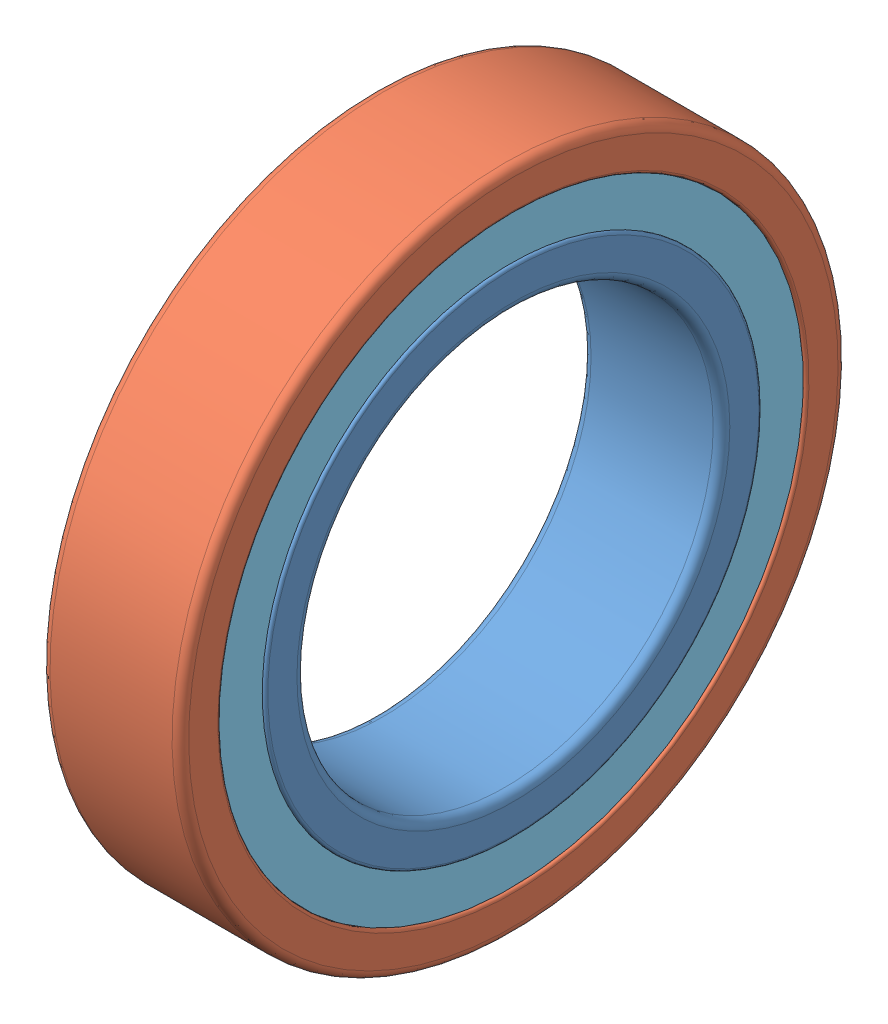
SolidWorks assembly 6802 2rs-, configuration Default. Lengths in mm.
Overall size (5 24 24).
19 component instances, 5 part files, 8 mates.
Components (placement in the parent):
- 6802 Inner race-1: 6802 Inner race [Default] at origin size (5 17.9 17.9)
- 6802 Outer race-1: 6802 Outer race [Default] at origin size (5 24 24)
- 6802 ball-1: 6802 ball [Default] at origin size (2.38 2.38 2.38)
- 6802 Cage-1: 6802 Cage [Default] at (2.5 0 0) x (0 0 -1) z (1 0 0) size (20.5 20.5 2.88)
- 6802 2rs-1: 6802 2rs [Default] at (0.1 0 0) x (0 0 -1) z (1 0 0) size (21.1 21.1 0.75)
- 6802 2rs-2: 6802 2rs [Default] at (4.15 0 0) x (0 0 -1) z (1 0 0) size (21.1 21.1 0.75)
- 6802 ball-15: 6802 ball [Default] x (1 0 0) z (0 -0.433884 0.900969) size (2.38 2.38 2.38)
- 6802 ball-16: 6802 ball [Default] x (1 0 0) z (0 -0.781831 0.62349) size (2.38 2.38 2.38)
- 6802 ball-17: 6802 ball [Default] x (1 0 0) z (0 -0.974928 0.222521) size (2.38 2.38 2.38)
- 6802 ball-18: 6802 ball [Default] x (1 0 0) z (0 -0.974928 -0.222521) size (2.38 2.38 2.38)
- 6802 ball-19: 6802 ball [Default] x (1 0 0) z (0 -0.781831 -0.62349) size (2.38 2.38 2.38)
- 6802 ball-20: 6802 ball [Default] x (1 0 0) z (0 -0.433884 -0.900969) size (2.38 2.38 2.38)
- 6802 ball-21: 6802 ball [Default] x (1 0 0) z (0 0 -1) size (2.38 2.38 2.38)
- 6802 ball-22: 6802 ball [Default] x (1 0 0) z (0 0.433884 -0.900969) size (2.38 2.38 2.38)
- 6802 ball-23: 6802 ball [Default] x (1 0 0) z (0 0.781831 -0.62349) size (2.38 2.38 2.38)
- 6802 ball-24: 6802 ball [Default] x (1 0 0) z (0 0.974928 -0.222521) size (2.38 2.38 2.38)
- 6802 ball-25: 6802 ball [Default] x (1 0 0) z (0 0.974928 0.222521) size (2.38 2.38 2.38)
- 6802 ball-26: 6802 ball [Default] x (1 0 0) z (0 0.781831 0.62349) size (2.38 2.38 2.38)
- 6802 ball-27: 6802 ball [Default] x (1 0 0) z (0 0.433884 0.900969) size (2.38 2.38 2.38)
Mates (geometry in assembly coordinates):
- InPlace1: in place: plane of 6802 Cage-1 through (2.5 0 0) normal (1 0 0); moOrthogonalPlaneRef_w of 6802 Cage-1 through (-55 2.5 0) axis (0 0 1); plane of 6802 Cage-1 through (2.5 0 0) normal (0 0 -1); unknown of 6802 Cage-1
- Coincident1: coincident aligned: 
- Coincident2: coincident aligned: plane of 6802 Cage-1 through (2.5 0 0) normal (0 1 0)
- Coincident3: coincident anti-aligned: plane of 6802 Cage-1 through (2.5 0 0) normal (0 0 -1)
- Concentric1: concentric anti-aligned: cylinder of 6802 Outer race-1 through (5 0 0) axis (1 0 0) radius 10.55; cylinder of 6802 2rs-1 through (0.85 0 0) axis (-1 0 0) radius 10.55
- Coincident1: coincident anti-aligned: circle of 6802 Outer race-1; plane of 6802 2rs-1 through (0.1 0 0) normal (-1 0 0)
- Concentric2: concentric anti-aligned: cylinder of 6802 Outer race-1 through (5 0 0) axis (1 0 0) radius 10.55; cylinder of 6802 2rs-2 through (4.9 0 0) axis (-1 0 0) radius 10.55
- Coincident2: coincident aligned: circle of 6802 Outer race-1; plane of 6802 2rs-2 through (4.9 0 0) normal (1 0 0)
